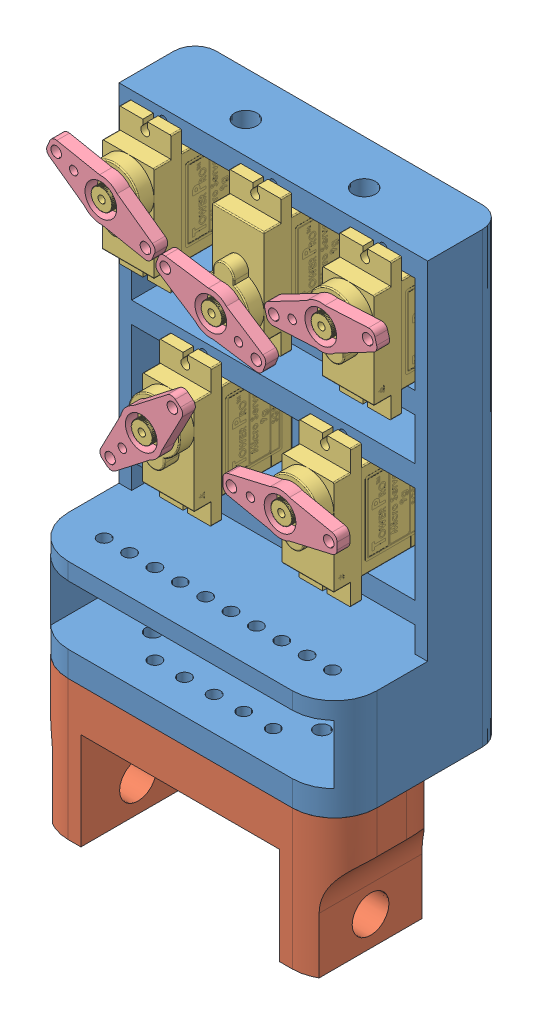
SolidWorks assembly Assem2, configuration Default. Lengths in mm.
Overall size (80.72 139 40).
12 component instances, 4 part files, 29 mates.
Components (placement in the parent):
- bed_servo-1: bed_servo [Default] at (3.448 24.1221 126.893) size (73 106 40)
- part_co_tay-1: part_co_tay [Default] at (76.448 24.1221 126.893) x (-1 0 0) z (0 0 1) size (73 33 27)
- User Library-SG90-3-1: User Library-SG90-3 [Default] at (-8.7124 72.2422 106.7192) x (0 1 0) z (1 0 0) size (32.36 29.6 12.25)
- User Library-SG90-3-2: User Library-SG90-3 [Default] at (33.7876 115.2422 106.7192) x (0 1 0) z (1 0 0) size (32.36 29.6 12.25)
- User Library-SG90-3-3: User Library-SG90-3 [Default] at (72.1084 112.0055 106.7192) x (0 -1 0) z (-1 0 0) size (32.36 29.6 12.25)
- User Library-SG90-3-4: User Library-SG90-3 [Default] at (-18.2124 115.2422 106.7192) x (0 1 0) z (1 0 0) size (32.36 29.6 12.25)
- User Library-SG90-3-5: User Library-SG90-3 [Default] at (24.2876 72.2422 106.7192) x (0 1 0) z (1 0 0) size (32.36 29.6 12.25)
- servo_tay-1: servo_tay [Default] at (65.948 118.7888 116.6773) x (0.96462 0.263646 0) z (0.263646 -0.96462 0) size (27 3 10)
- servo_tay-2: servo_tay [Default] at (39.948 108.459 116.6773) x (-0.935624 0.352998 0) z (0.352998 0.935624 0) size (27 3 10)
- servo_tay-3: servo_tay [Default] at (23.448 75.7888 116.6169) x (0.640493 0.767964 0) z (0.767964 -0.640493 0) size (27 3 10)
- servo_tay-4: servo_tay [Default] at (13.948 118.7888 116.6773) x (0.917487 -0.397766 0) z (-0.397766 -0.917487 0) size (27 3 10)
- servo_tay-5: servo_tay [Default] at (56.448 75.7888 116.798) x (0.999942 0.010793 0) z (0.010793 -0.999942 0) size (27 3 10)
Mates (geometry in assembly coordinates):
- Concentric1: concentric anti-aligned: cylinder of bed_servo-1 through (59.948 130.1231 113.393) axis (0 -1 0) radius 1.75; cylinder of part_co_tay-1 through (59.948 -5.8779 113.393) axis (0 1 0) radius 1.75
- Concentric2: concentric anti-aligned: cylinder of bed_servo-1 through (19.948 130.1231 113.393) axis (0 -1 0) radius 1.75; cylinder of part_co_tay-1 through (19.948 -5.8779 113.393) axis (0 1 0) radius 1.75
- Coincident1: coincident anti-aligned: plane of bed_servo-1 through (3.448 24.1221 126.893) normal (0 -1 0); plane of part_co_tay-1 through (76.448 24.1221 126.893) normal (0 1 0)
- Coincident2: coincident anti-aligned: plane of bed_servo-1 through (3.448 24.1221 89.893) normal (0 0 1); plane of User Library-SG90-3-1 through (29.548 81.8888 89.893) normal (0 0 -1)
- Coincident4: coincident anti-aligned: plane of bed_servo-1 through (3.448 24.1221 89.893) normal (0 0 1); plane of User Library-SG90-3-2 through (72.048 124.8888 89.893) normal (0 0 -1)
- Parallel1: parallel aligned: cylinder of bed_servo-1 through (65.948 127.6221 94.893) axis (0 0 1) radius 1; cylinder of User Library-SG90-3-2 through (65.948 127.6256 89.893) axis (0 0 1) radius 1.0478
- Parallel2: parallel aligned: cylinder of bed_servo-1 through (65.948 127.6221 94.893) axis (0 0 1) radius 1; cylinder of User Library-SG90-3-2 through (65.948 127.6256 89.893) axis (0 0 1) radius 1.0478
- Coincident7: coincident anti-aligned: plane of bed_servo-1 through (3.448 24.1221 89.893) normal (0 0 1); plane of User Library-SG90-3-3 through (33.848 102.359 89.893) normal (0 0 -1)
- Coincident9: coincident anti-aligned: plane of bed_servo-1 through (3.448 24.1221 89.893) normal (0 0 1); plane of User Library-SG90-3-4 through (20.048 124.8888 89.893) normal (0 0 -1)
- Coincident12: coincident anti-aligned: plane of bed_servo-1 through (3.448 24.1221 89.893) normal (0 0 1); plane of User Library-SG90-3-5 through (62.548 81.8888 89.893) normal (0 0 -1)
- Concentric5: concentric aligned: cylinder of bed_servo-1 through (56.448 56.6221 94.893) axis (0 0 1) radius 1; cylinder of User Library-SG90-3-5 through (56.448 56.6221 89.893) axis (0 0 1) radius 1.0478
- Parallel3: parallel aligned: cylinder of bed_servo-1 through (23.448 56.6221 94.893) axis (0 0 1) radius 1; cylinder of User Library-SG90-3-1 through (23.448 56.6221 89.893) axis (0 0 1) radius 1.0478
- Concentric7: concentric aligned: cylinder of bed_servo-1 through (65.948 99.6221 94.893) axis (0 0 1) radius 1; cylinder of User Library-SG90-3-2 through (65.948 99.6221 89.893) axis (0 0 1) radius 1.0478
- Concentric8: concentric aligned: cylinder of bed_servo-1 through (39.948 99.6221 94.893) axis (0 0 1) radius 1; cylinder of User Library-SG90-3-3 through (39.948 99.6221 89.893) axis (0 0 1) radius 1.0478
- Concentric9: concentric aligned: cylinder of bed_servo-1 through (13.948 99.6221 94.893) axis (0 0 1) radius 1; cylinder of User Library-SG90-3-4 through (13.948 99.6221 89.893) axis (0 0 1) radius 1.0478
- Concentric10: concentric aligned: cylinder of bed_servo-1 through (23.448 56.6221 94.893) axis (0 0 1) radius 1; cylinder of User Library-SG90-3-1 through (23.448 56.6221 89.893) axis (0 0 1) radius 1.0478
- Concentric11: concentric anti-aligned: cylinder of User Library-SG90-3-2 through (65.948 118.7888 115.6867) axis (0 0 1) radius 0.8573; cylinder of servo_tay-1 through (65.948 118.7888 119.6773) axis (0 0 -1) radius 3.75
- Concentric12: concentric anti-aligned: cylinder of User Library-SG90-3-3 through (39.948 108.459 115.6867) axis (0 0 1) radius 0.8573; cylinder of servo_tay-2 through (39.948 108.459 119.6773) axis (0 0 -1) radius 3.75
- Concentric13: concentric anti-aligned: cylinder of User Library-SG90-3-4 through (13.948 118.7888 115.6867) axis (0 0 1) radius 0.8573; cylinder of servo_tay-4 through (13.948 118.7888 119.6773) axis (0 0 -1) radius 3.75
- Concentric14: concentric aligned: cylinder of User Library-SG90-3-1 through (23.448 75.7888 115.6867) axis (0 0 1) radius 0.8573; circle of servo_tay-3
- Coincident14: coincident anti-aligned: plane of User Library-SG90-3-4 through (20.048 124.8888 116.6773) normal (0 0 1); plane of servo_tay-4 through (13.948 118.7888 116.6773) normal (0 0 -1)
- Parallel5: parallel anti-aligned: plane of bed_servo-1 through (76.448 125.1221 104.893) normal (0 -1 0); plane of User Library-SG90-3-4 through (20.048 124.8888 106.693) normal (0 1 0)
- Concentric16: concentric anti-aligned: cylinder of User Library-SG90-3-5 through (56.448 75.7888 115.6867) axis (0 0 1) radius 0.8573; cylinder of servo_tay-5 through (56.448 75.7888 119.798) axis (0 0 -1) radius 3.75
- Coincident15: coincident anti-aligned: plane of User Library-SG90-3-2 through (72.048 124.8888 116.6773) normal (0 0 1); plane of servo_tay-1 through (65.948 118.7888 116.6773) normal (0 0 -1)
- Coincident16: coincident anti-aligned: plane of User Library-SG90-3-3 through (33.848 102.359 116.6773) normal (0 0 1); plane of servo_tay-2 through (39.948 108.459 116.6773) normal (0 0 -1)
- Parallel6: parallel anti-aligned: plane of bed_servo-1 through (76.448 125.1221 104.893) normal (0 -1 0); plane of User Library-SG90-3-3 through (33.848 124.8888 89.893) normal (0 1 0)
- Parallel7: parallel anti-aligned: plane of bed_servo-1 through (76.448 125.1221 104.893) normal (0 -1 0); plane of User Library-SG90-3-2 through (72.048 124.8888 106.693) normal (0 1 0)
- Parallel8: parallel anti-aligned: plane of bed_servo-1 through (76.448 82.1221 104.893) normal (0 -1 0); plane of User Library-SG90-3-5 through (62.548 81.8888 106.693) normal (0 1 0)
- Parallel9: parallel anti-aligned: plane of bed_servo-1 through (76.448 82.1221 104.893) normal (0 -1 0); plane of User Library-SG90-3-1 through (29.548 81.8888 106.693) normal (0 1 0)
